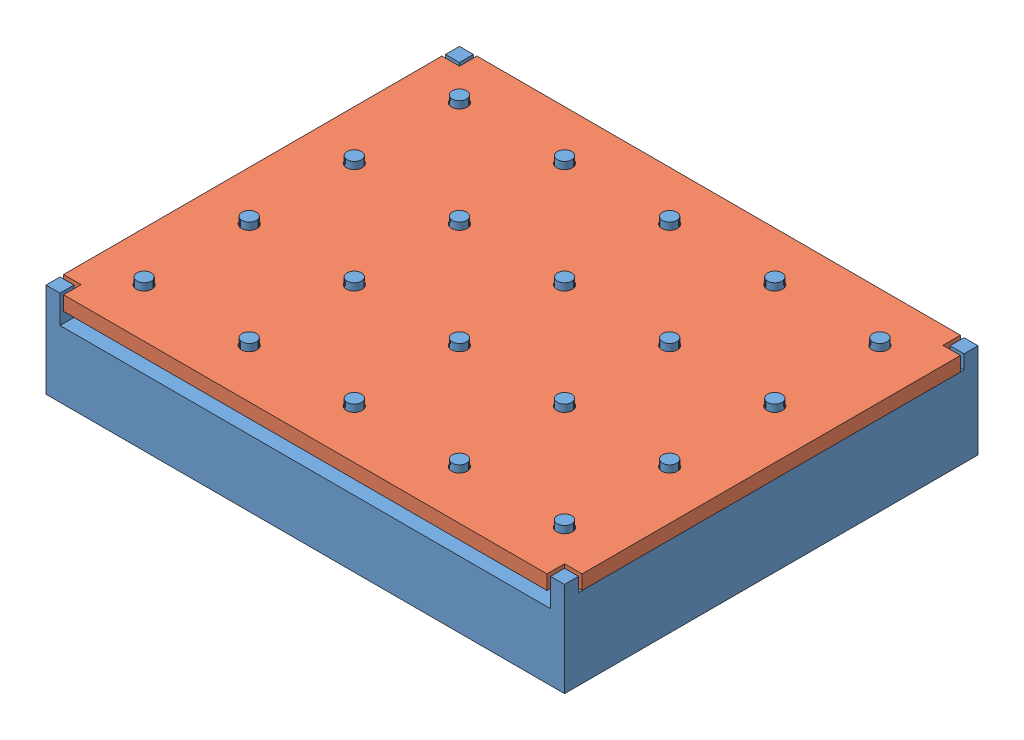
SolidWorks assembly Assem1, configuration Default. Lengths in mm.
Overall size (75.18 14.73 59.94).
2 component instances, 2 part files, 3 mates.
Components (placement in the parent):
- numpad_big_bottom-1: numpad_big_bottom [Default] at (14.8383 27.9886 70.5027) size (75.18 14.73 59.94)
- numpad_big_top-1: numpad_big_top [Default] at (-1.0367 41.7554 24.1477) x (1 0 0) z (0 0 -1) size (75.18 5.66 59.94)
Mates (geometry in assembly coordinates):
- Coincident4: coincident anti-aligned: plane of numpad_big_bottom-1 through (14.8383 39.6726 70.5027) normal (0 1 0); plane of numpad_big_top-1 through (-1.0367 39.6726 24.1477) normal (0 -1 0)
- Concentric1: concentric anti-aligned: circle of numpad_big_bottom-1; circle of numpad_big_top-1
- Concentric2: concentric anti-aligned: circle of numpad_big_bottom-1; circle of numpad_big_top-1
